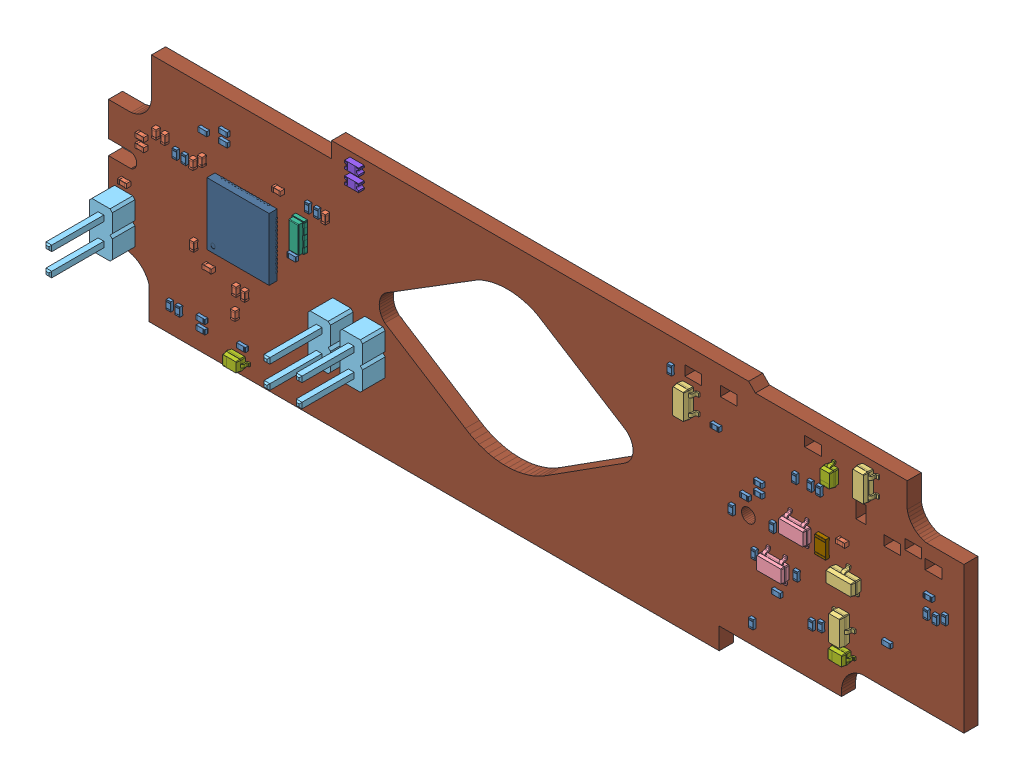
SolidWorks assembly opsx_x, configuration 默认. Lengths in mm.
Overall size (95.88 27.81 11.54).
134 component instances, 11 part files, 0 mates.
Components (placement in the parent):
- opsx_x.step-1: opsx_x.step [默认] at origin size (95.88 27.81 11.54)
  - R_0402_1005Metric.step-1: R_0402_1005Metric.step [默认] at (22.6 20.3 1.63) x (0 -1 0) z (0 0 1) size (1 0.5 0.35)
    - SOLID.step-1: SOLID.step [默认] at origin size (1 0.5 0.35)
  - R_0402_1005Metric.step-2: R_0402_1005Metric.step [默认] at (20.875 14.65 1.63) x (-1 0 0) z (0 0 1) size (1 0.5 0.35)
    - SOLID.step-1: SOLID.step [默认] at origin size (1 0.5 0.35)
  - C_0402_1005Metric.step-1: C_0402_1005Metric.step [默认] at (6.625 19.05 1.63) x (0 1 0) z (0 0 1) size (1 0.5 0.5)
    - SOLID-0.step-1: SOLID-0.step [默认] at origin size (1 0.5 0.5)
  - R_0402_1005Metric.step-3: R_0402_1005Metric.step [默认] at (13.2 21.9 1.63) size (1 0.5 0.35)
    - SOLID.step-1: SOLID.step [默认] at origin size (1 0.5 0.35)
  - R_0402_1005Metric.step-4: R_0402_1005Metric.step [默认] at (75.184 9.146 1.63) x (-1 0 0) z (0 0 1) size (1 0.5 0.35)
    - SOLID.step-1: SOLID.step [默认] at origin size (1 0.5 0.35)
  - R_0402_1005Metric.step-5: R_0402_1005Metric.step [默认] at (10.922 21.846 1.63) size (1 0.5 0.35)
    - SOLID.step-1: SOLID.step [默认] at origin size (1 0.5 0.35)
  - R_0402_1005Metric.step-6: R_0402_1005Metric.step [默认] at (7.784 18.1 1.63) x (0 1 0) z (0 0 1) size (1 0.5 0.35)
    - SOLID.step-1: SOLID.step [默认] at origin size (1 0.5 0.35)
  - SOT-23.step-1: SOT-23.step [默认] at (83.058 14.48 1.63) x (0 1 0) z (0 0 1) size (2.5 3 1.2)
    - SOLID-1.step-1: SOLID-1.step [默认] at origin size (2.5 3 1.2)
  - R_0402_1005Metric.step-7: R_0402_1005Metric.step [默认] at (72.644 11.686 1.63) x (0 -1 0) z (0 0 1) size (1 0.5 0.35)
    - SOLID.step-1: SOLID.step [默认] at origin size (1 0.5 0.35)
  - TSOT-23-5.step-1: TSOT-23-5.step [默认] at (75.025 11.686 1.63) x (0 1 0) z (0 0 1) size (2.8 2.9 0.95)
    - SOLID-2.step-1: SOLID-2.step [默认] at origin size (2.8 2.9 0.95)
  - SOT-23.step-2: SOT-23.step [默认] at (85.25 25 1.63) x (-1 0 0) z (0 0 1) size (2.5 3 1.2)
    - SOLID-1.step-1: SOLID-1.step [默认] at origin size (2.5 3 1.2)
  - R_0402_1005Metric.step-8: R_0402_1005Metric.step [默认] at (79.925 21.475 1.63) x (0 1 0) z (0 0 1) size (1 0.5 0.35)
    - SOLID.step-1: SOLID.step [默认] at origin size (1 0.5 0.35)
  - SOT-23.step-3: SOT-23.step [默认] at (82.575 9.65 1.63) size (2.5 3 1.2)
    - SOLID-1.step-1: SOLID-1.step [默认] at origin size (2.5 3 1.2)
  - R_0402_1005Metric.step-9: R_0402_1005Metric.step [默认] at (71.628 16.766 1.63) x (-1 0 0) z (0 0 1) size (1 0.5 0.35)
    - SOLID.step-1: SOLID.step [默认] at origin size (1 0.5 0.35)
  - PinHeader_1x02_P2.54mm_Vertical.step-1: PinHeader_1x02_P2.54mm_Vertical.step [默认] at (1.75 7.575 1.63) x (-1 0 0) z (0 0 1) size (2.54 5.08 11.54)
    - SOLID-3.step-1: SOLID-3.step [默认] at origin size (2.54 5.08 11.54)
  - SOT-23.step-4: SOT-23.step [默认] at (65.1025 22.928 1.63) x (-1 0 0) z (0 0 1) size (2.5 3 1.2)
    - SOLID-1.step-1: SOLID-1.step [默认] at origin size (2.5 3 1.2)
  - C_0402_1005Metric.step-2: C_0402_1005Metric.step [默认] at (82.55 17.782 1.63) size (1 0.5 0.5)
    - SOLID-0.step-1: SOLID-0.step [默认] at origin size (1 0.5 0.5)
  - C_0402_1005Metric.step-3: C_0402_1005Metric.step [默认] at (14.484 5.9 1.63) x (0 -1 0) z (0 0 1) size (1 0.5 0.5)
    - SOLID-0.step-1: SOLID-0.step [默认] at origin size (1 0.5 0.5)
  - C_0402_1005Metric.step-4: C_0402_1005Metric.step [默认] at (2.05 12.45 1.63) x (-1 0 0) z (0 0 1) size (1 0.5 0.5)
    - SOLID-0.step-1: SOLID-0.step [默认] at origin size (1 0.5 0.5)
  - R_0402_1005Metric.step-10: R_0402_1005Metric.step [默认] at (68.326 21.846 1.63) size (1 0.5 0.35)
    - SOLID.step-1: SOLID.step [默认] at origin size (1 0.5 0.35)
  - R_0402_1005Metric.step-11: R_0402_1005Metric.step [默认] at (77.35 11.94 1.63) x (0 -1 0) z (0 0 1) size (1 0.5 0.35)
    - SOLID.step-1: SOLID.step [默认] at origin size (1 0.5 0.35)
  - C_0402_1005Metric.step-5: C_0402_1005Metric.step [默认] at (5.625 19.075 1.63) x (0 1 0) z (0 0 1) size (1 0.5 0.5)
    - SOLID-0.step-1: SOLID-0.step [默认] at origin size (1 0.5 0.5)
  - R_0402_1005Metric.step-12: R_0402_1005Metric.step [默认] at (63.246 24.894 1.63) x (0 -1 0) z (0 0 1) size (1 0.5 0.35)
    - SOLID.step-1: SOLID.step [默认] at origin size (1 0.5 0.35)
  - R_0402_1005Metric.step-13: R_0402_1005Metric.step [默认] at (70.104 14.734 1.63) x (0 -1 0) z (0 0 1) size (1 0.5 0.35)
    - SOLID.step-1: SOLID.step [默认] at origin size (1 0.5 0.35)
  - R_0402_1005Metric.step-14: R_0402_1005Metric.step [默认] at (72.39 4.828 1.63) x (0 -1 0) z (0 0 1) size (1 0.5 0.35)
    - SOLID.step-1: SOLID.step [默认] at origin size (1 0.5 0.35)
  - C_0402_1005Metric.step-6: C_0402_1005Metric.step [默认] at (24.6 20.325 1.63) x (0 1 0) z (0 0 1) size (1 0.5 0.5)
    - SOLID-0.step-1: SOLID-0.step [默认] at origin size (1 0.5 0.5)
  - R_0402_1005Metric.step-15: R_0402_1005Metric.step [默认] at (10.7025 2.5 1.63) x (-1 0 0) z (0 0 1) size (1 0.5 0.35)
    - SOLID.step-1: SOLID.step [默认] at origin size (1 0.5 0.35)
  - R_0402_1005Metric.step-16: R_0402_1005Metric.step [默认] at (73.152 17.782 1.63) size (1 0.5 0.35)
    - SOLID.step-1: SOLID.step [默认] at origin size (1 0.5 0.35)
  - C_0402_1005Metric.step-7: C_0402_1005Metric.step [默认] at (19.304 20.322 1.63) size (1 0.5 0.5)
    - SOLID-0.step-1: SOLID-0.step [默认] at origin size (1 0.5 0.5)
  - R_0402_1005Metric.step-17: R_0402_1005Metric.step [默认] at (80.1 8.384 1.63) x (0 1 0) z (0 0 1) size (1 0.5 0.35)
    - SOLID.step-1: SOLID.step [默认] at origin size (1 0.5 0.35)
  - TSOT-23-5.step-2: TSOT-23-5.step [默认] at (77.47 16.512 1.63) x (0 1 0) z (0 0 1) size (2.8 2.9 0.95)
    - SOLID-2.step-1: SOLID-2.step [默认] at origin size (2.8 2.9 0.95)
  - Resonator_SMD_Murata_CSTxExxV-3Pin_3.0x1.1mm.step-1: Resonator_SMD_Murata_CSTxExxV-3Pin_3.0x1.1mm.step [默认] at (21.7 17.25 1.63) x (0 1 0) z (0 0 1) size (3.2 1.35 0.9)
    - SOLID-4.step-1: SOLID-4.step [默认] at origin size (3.2 1.35 0.9)
  - D_SOD-323.step-1: D_SOD-323.step [默认] at (81.425 23.8 1.63) x (0 1 0) z (0 0 1) size (2.5 1.25 1.1)
    - SOLID-5.step-1: SOLID-5.step [默认] at origin size (2.5 1.25 1.1)
  - R_0402_1005Metric.step-18: R_0402_1005Metric.step [默认] at (93.98 16.004 1.63) x (0 -1 0) z (0 0 1) size (1 0.5 0.35)
    - SOLID.step-1: SOLID.step [默认] at origin size (1 0.5 0.35)
  - R_0402_1005Metric.step-19: R_0402_1005Metric.step [默认] at (10.7025 3.5 1.63) size (1 0.5 0.35)
    - SOLID.step-1: SOLID.step [默认] at origin size (1 0.5 0.35)
  - R_0402_1005Metric.step-20: R_0402_1005Metric.step [默认] at (91.932 15.4985 1.63) x (0 -1 0) z (0 0 1) size (1 0.5 0.35)
    - SOLID.step-1: SOLID.step [默认] at origin size (1 0.5 0.35)
  - D_0603_1608Metric.step-1: D_0603_1608Metric.step [默认] at (27.94 25.402 1.63) x (-1 0 0) z (0 0 1) size (1.6 0.87 0.66)
    - SOLID-6.step-1: SOLID-6.step [默认] at origin size (1.6 0.87 0.66)
  - PinHeader_1x02_P2.54mm_Vertical.step-2: PinHeader_1x02_P2.54mm_Vertical.step [默认] at (29.8 11.425 1.63) size (2.54 5.08 11.54)
    - SOLID-3.step-1: SOLID-3.step [默认] at origin size (2.54 5.08 11.54)
  - D_0603_1608Metric.step-2: D_0603_1608Metric.step [默认] at (27.94 26.926 1.63) x (-1 0 0) z (0 0 1) size (1.6 0.87 0.66)
    - SOLID-6.step-1: SOLID-6.step [默认] at origin size (1.6 0.87 0.66)
  - R_0402_1005Metric.step-21: R_0402_1005Metric.step [默认] at (23.625 20.3 1.63) x (0 1 0) z (0 0 1) size (1 0.5 0.35)
    - SOLID.step-1: SOLID.step [默认] at origin size (1 0.5 0.35)
  - R_0402_1005Metric.step-22: R_0402_1005Metric.step [默认] at (92.202 17.274 1.63) size (1 0.5 0.35)
    - SOLID.step-1: SOLID.step [默认] at origin size (1 0.5 0.35)
  - R_0402_1005Metric.step-23: R_0402_1005Metric.step [默认] at (74.7 15.325 1.63) x (0 -1 0) z (0 0 1) size (1 0.5 0.35)
    - SOLID.step-1: SOLID.step [默认] at origin size (1 0.5 0.35)
  - C_0402_1005Metric.step-8: C_0402_1005Metric.step [默认] at (4 17.9 1.63) x (-1 0 0) z (0 0 1) size (1 0.5 0.5)
    - SOLID-0.step-1: SOLID-0.step [默认] at origin size (1 0.5 0.5)
  - D_SOD-323.step-2: D_SOD-323.step [默认] at (82.575 7 1.63) size (2.5 1.25 1.1)
    - SOLID-5.step-1: SOLID-5.step [默认] at origin size (2.5 1.25 1.1)
  - R_0402_1005Metric.step-24: R_0402_1005Metric.step [默认] at (77.216 21.338 1.63) x (0 -1 0) z (0 0 1) size (1 0.5 0.35)
    - SOLID.step-1: SOLID.step [默认] at origin size (1 0.5 0.35)
  - D_SOD-323.step-3: D_SOD-323.step [默认] at (14.7 1.6 1.63) size (2.5 1.25 1.1)
    - SOLID-5.step-1: SOLID-5.step [默认] at origin size (2.5 1.25 1.1)
  - R_0402_1005Metric.step-25: R_0402_1005Metric.step [默认] at (78.925 21.45 1.63) x (0 -1 0) z (0 0 1) size (1 0.5 0.35)
    - SOLID.step-1: SOLID.step [默认] at origin size (1 0.5 0.35)
  - C_0402_1005Metric.step-9: C_0402_1005Metric.step [默认] at (9.85 10.3 1.63) x (0 -1 0) z (0 0 1) size (1 0.5 0.5)
    - SOLID-0.step-1: SOLID-0.step [默认] at origin size (1 0.5 0.5)
  - C_0402_1005Metric.step-10: C_0402_1005Metric.step [默认] at (9.775 18.2 1.63) x (0 1 0) z (0 0 1) size (1 0.5 0.5)
    - SOLID-0.step-1: SOLID-0.step [默认] at origin size (1 0.5 0.5)
  - R_0402_1005Metric.step-26: R_0402_1005Metric.step [默认] at (8.8 18.1 1.63) x (0 1 0) z (0 0 1) size (1 0.5 0.35)
    - SOLID.step-1: SOLID.step [默认] at origin size (1 0.5 0.35)
  - R_0805_2012Metric.step-1: R_0805_2012Metric.step [默认] at (80.264 16.258 1.63) x (0 -1 0) z (0 0 1) size (2 1.2 0.45)
    - SOLID-7.step-1: SOLID-7.step [默认] at origin size (2 1.2 0.45)
  - R_0402_1005Metric.step-27: R_0402_1005Metric.step [默认] at (87.5275 10.416 1.63) size (1 0.5 0.35)
    - SOLID.step-1: SOLID.step [默认] at origin size (1 0.5 0.35)
  - PinHeader_1x02_P2.54mm_Vertical.step-3: PinHeader_1x02_P2.54mm_Vertical.step [默认] at (26.2 11.425 1.63) size (2.54 5.08 11.54)
    - SOLID-3.step-1: SOLID-3.step [默认] at origin size (2.54 5.08 11.54)
  - R_0402_1005Metric.step-28: R_0402_1005Metric.step [默认] at (13.2 22.9 1.63) size (1 0.5 0.35)
    - SOLID.step-1: SOLID.step [默认] at origin size (1 0.5 0.35)
  - R_0402_1005Metric.step-29: R_0402_1005Metric.step [默认] at (15.24 3.05 1.63) x (-1 0 0) z (0 0 1) size (1 0.5 0.35)
    - SOLID.step-1: SOLID.step [默认] at origin size (1 0.5 0.35)
  - R_0402_1005Metric.step-30: R_0402_1005Metric.step [默认] at (8.128 3.05 1.63) x (0 1 0) z (0 0 1) size (1 0.5 0.35)
    - SOLID.step-1: SOLID.step [默认] at origin size (1 0.5 0.35)
  - R_0402_1005Metric.step-31: R_0402_1005Metric.step [默认] at (73.152 18.798 1.63) x (-1 0 0) z (0 0 1) size (1 0.5 0.35)
    - SOLID.step-1: SOLID.step [默认] at origin size (1 0.5 0.35)
  - C_0402_1005Metric.step-11: C_0402_1005Metric.step [默认] at (4 16.9 1.63) x (-1 0 0) z (0 0 1) size (1 0.5 0.5)
    - SOLID-0.step-1: SOLID-0.step [默认] at origin size (1 0.5 0.5)
  - R_0402_1005Metric.step-32: R_0402_1005Metric.step [默认] at (92.964 15.496 1.63) x (0 1 0) z (0 0 1) size (1 0.5 0.35)
    - SOLID.step-1: SOLID.step [默认] at origin size (1 0.5 0.35)
  - C_0402_1005Metric.step-12: C_0402_1005Metric.step [默认] at (14.6 8.3 1.63) x (0 -1 0) z (0 0 1) size (1 0.5 0.5)
    - SOLID-0.step-1: SOLID-0.step [默认] at origin size (1 0.5 0.5)
  - C_0402_1005Metric.step-13: C_0402_1005Metric.step [默认] at (10.775 18.975 1.63) x (0 1 0) z (0 0 1) size (1 0.5 0.5)
    - SOLID-0.step-1: SOLID-0.step [默认] at origin size (1 0.5 0.5)
  - C_0402_1005Metric.step-14: C_0402_1005Metric.step [默认] at (11.55 8.9 1.63) x (-1 0 0) z (0 0 1) size (1 0.5 0.5)
    - SOLID-0.step-1: SOLID-0.step [默认] at origin size (1 0.5 0.5)
  - QFN-56-1EP_7x7mm_P0.4mm_EP5.6x5.6mm.step-1: QFN-56-1EP_7x7mm_P0.4mm_EP5.6x5.6mm.step [默认] at (15.4875 14.7375 1.63) x (0 1 0) z (0 0 1) size (7 7 0.92)
    - SOLID-8.step-1: SOLID-8.step [默认] at origin size (7 7 0.92)
  - R_0402_1005Metric.step-33: R_0402_1005Metric.step [默认] at (7.112 3.05 1.63) x (0 1 0) z (0 0 1) size (1 0.5 0.35)
    - SOLID.step-1: SOLID.step [默认] at origin size (1 0.5 0.35)
  - R_0402_1005Metric.step-34: R_0402_1005Metric.step [默认] at (79.075 8.034 1.63) x (0 1 0) z (0 0 1) size (1 0.5 0.35)
    - SOLID.step-1: SOLID.step [默认] at origin size (1 0.5 0.35)
  - C_0402_1005Metric.step-15: C_0402_1005Metric.step [默认] at (15.575 8.3 1.63) x (0 -1 0) z (0 0 1) size (1 0.5 0.5)
    - SOLID-0.step-1: SOLID-0.step [默认] at origin size (1 0.5 0.5)
  - PCB.step-1: PCB.step [默认] at origin size (95.88 27.81 1.58)
